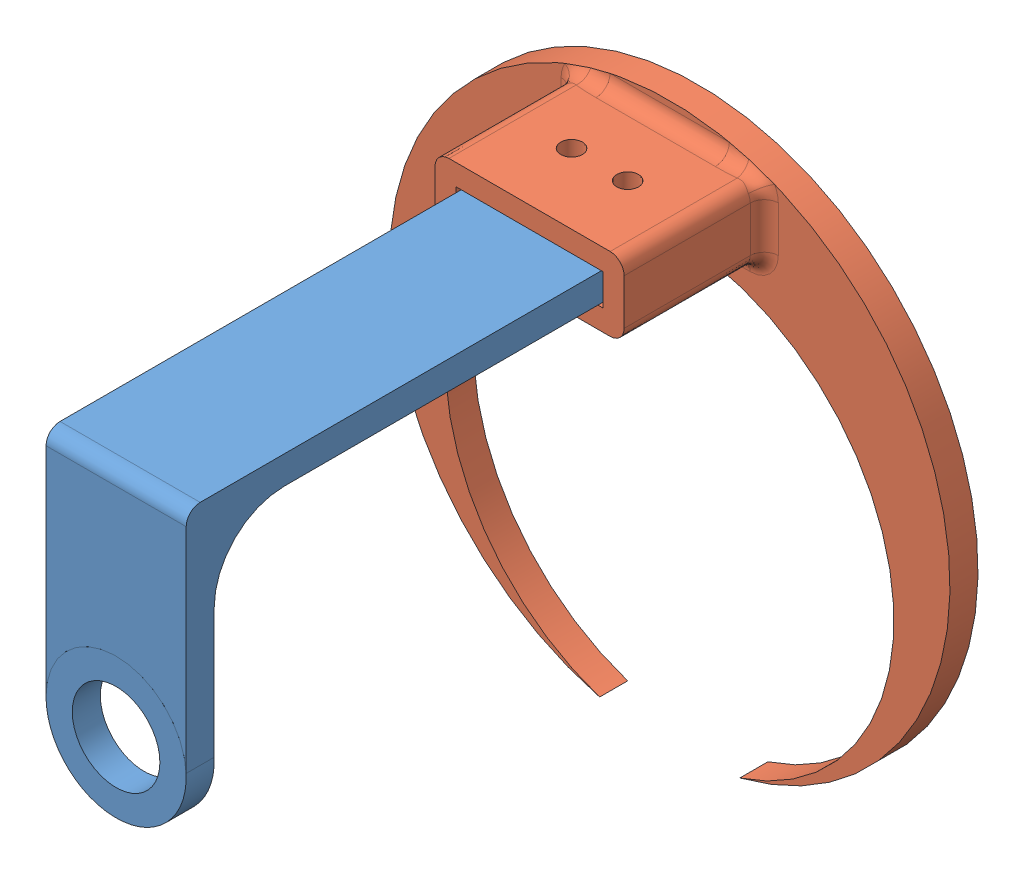
SolidWorks assembly Ensamblaje1, configuration Predeterminado. Lengths in mm.
Overall size (80 78.73 83).
2 component instances, 2 part files, 2 mates.
Components (placement in the parent):
- Sensor-1: Sensor [Predeterminado] at (-36.7997 -63.1412 109.4927) size (20 43 74)
- bas2-1: bas2 [Predeterminado] at (-21.7997 -77.7003 30.4927) x (1 0 0) z (0 -1 0) size (80 24 78.73)
Mates (geometry in assembly coordinates):
- Concéntrica1: concentric aligned: cylinder of Sensor-1 through (-32.7997 -40.1412 44.4927) axis (0 1 0) radius 1.6; cylinder of bas2-1 through (-32.7997 -56.8353 44.4927) axis (0 1 0) radius 1.55
- Concéntrica2: concentric aligned: cylinder of Sensor-1 through (-40.7997 -40.1412 44.4927) axis (0 1 0) radius 1.6; cylinder of bas2-1 through (-40.7997 -56.8353 44.4927) axis (0 1 0) radius 1.55
